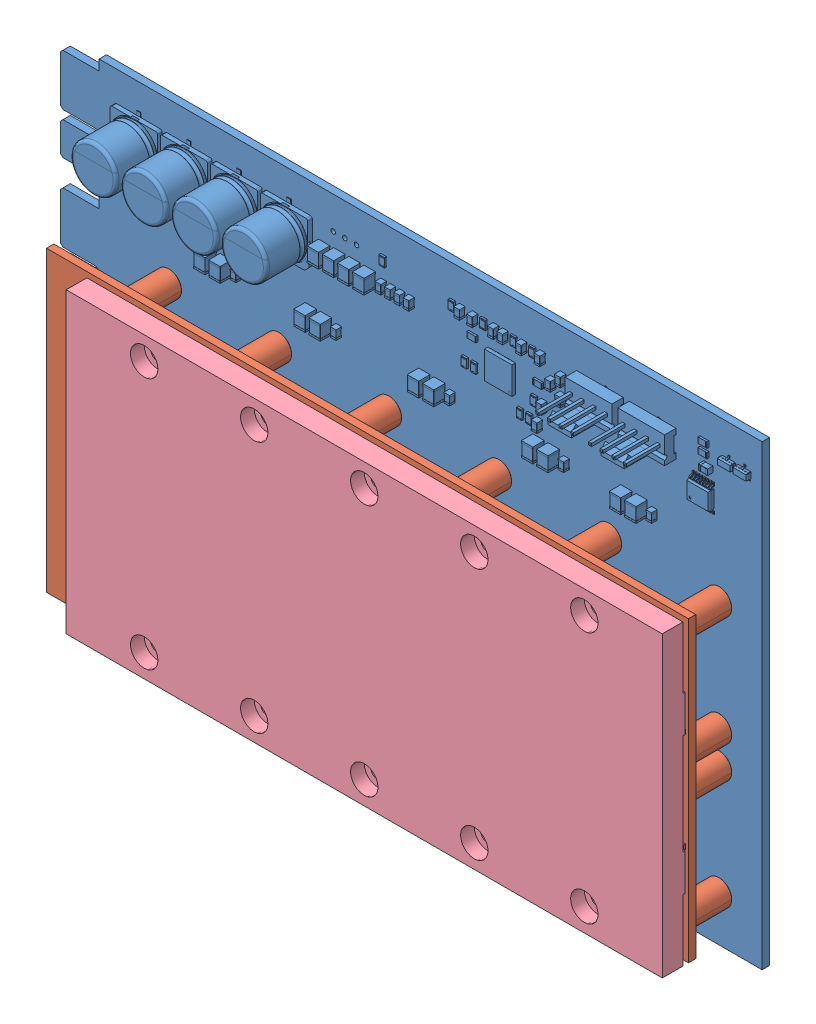
SolidWorks assembly EKO_Miner build 16xBM1366 V1.00, configuration Défaut. Lengths in mm.
Overall size (153 99.75 24.4).
5 component instances, 4 part files, 10 mates.
Components (placement in the parent):
- EKO_Miner_PowerBoard_TPS53667_01A-1: EKO_Miner_PowerBoard_TPS53667_01A [Défaut] at (-184.988 66.2219 -3.14) size (153 99.75 17.02)
- EKO_Miner_AsicBoard-16xBM1366-01A-1: EKO_Miner_AsicBoard-16xBM1366-01A [Défaut] at (-109.988 -53.7781 8.59) size (140 65 12.43)
- CHC3 M3x6mm-1: CHC3 M3x6mm [M3X6mm] at (25.012 -48.7781 -6.14) x (-0.999691 -0.02485 0) z (0 0 -1) size (5.5 5.5 9.19)
- CHC3 M3x6mm-2: CHC3 M3x6mm [M3X6mm] at (-94.988 6.2219 -6.14) x (-0.877744 -0.47913 0) z (0 0 -1) size (5.5 5.5 9.19)
- EKO_Miner_AsicBoard-16xBM1366-01A Heatsink-1: EKO_Miner_AsicBoard-16xBM1366-01A Heatsink [Défaut] at (-99.988 -53.7781 10.89) size (130 65 5)
Mates (geometry in assembly coordinates):
- Coaxiale1: concentric aligned: circle of EKO_Miner_PowerBoard_TPS53667_01A-1; circle of EKO_Miner_AsicBoard-16xBM1366-01A-1
- Coaxiale2: concentric aligned: circle of EKO_Miner_PowerBoard_TPS53667_01A-1; circle of EKO_Miner_AsicBoard-16xBM1366-01A-1
- Coïncidente1: coincident anti-aligned: plane of EKO_Miner_PowerBoard_TPS53667_01A-1 through (-184.988 66.2219 -1.54) normal (0 0 1); plane of EKO_Miner_AsicBoard-16xBM1366-01A-1 through (23.6637 -48.7781 -1.54) normal (0 0 -1)
- Coaxiale3: concentric aligned: cylinder of EKO_Miner_PowerBoard_TPS53667_01A-1 through (25.012 -48.7781 -3.185) axis (0 0 -1) radius 1.6; circle of CHC3 M3x6mm-1
- Coïncidente2: coincident anti-aligned: plane of EKO_Miner_PowerBoard_TPS53667_01A-1 through (-184.988 66.2219 -3.14) normal (0 0 -1); plane of CHC3 M3x6mm-1 through (24.949 -46.2439 -3.14) normal (0 0 1)
- Coaxiale4: concentric aligned: circle of EKO_Miner_PowerBoard_TPS53667_01A-1; circle of CHC3 M3x6mm-2
- Coïncidente3: coincident anti-aligned: plane of EKO_Miner_PowerBoard_TPS53667_01A-1 through (-184.988 66.2219 -3.14) normal (0 0 -1); plane of CHC3 M3x6mm-2 through (-96.2026 8.447 -3.14) normal (0 0 1)
- Coaxiale5: concentric aligned: circle of EKO_Miner_AsicBoard-16xBM1366-01A-1; cylinder of EKO_Miner_AsicBoard-16xBM1366-01A Heatsink-1 through (-82.988 -48.7781 15.89) axis (0 0 -1) radius 1.6
- Coaxiale6: concentric: circle of EKO_Miner_AsicBoard-16xBM1366-01A-1; cylinder of EKO_Miner_AsicBoard-16xBM1366-01A Heatsink-1 through (13.012 6.2219 15.89) axis (0 0 -1) radius 1.6
- Coïncidente6: coincident: plane of EKO_Miner_AsicBoard-16xBM1366-01A-1 through (22.6 -5.6451 10.89) normal (0 0 1); plane of EKO_Miner_AsicBoard-16xBM1366-01A Heatsink-1 through (-99.988 -53.7781 10.89) normal (0 0 -1)
